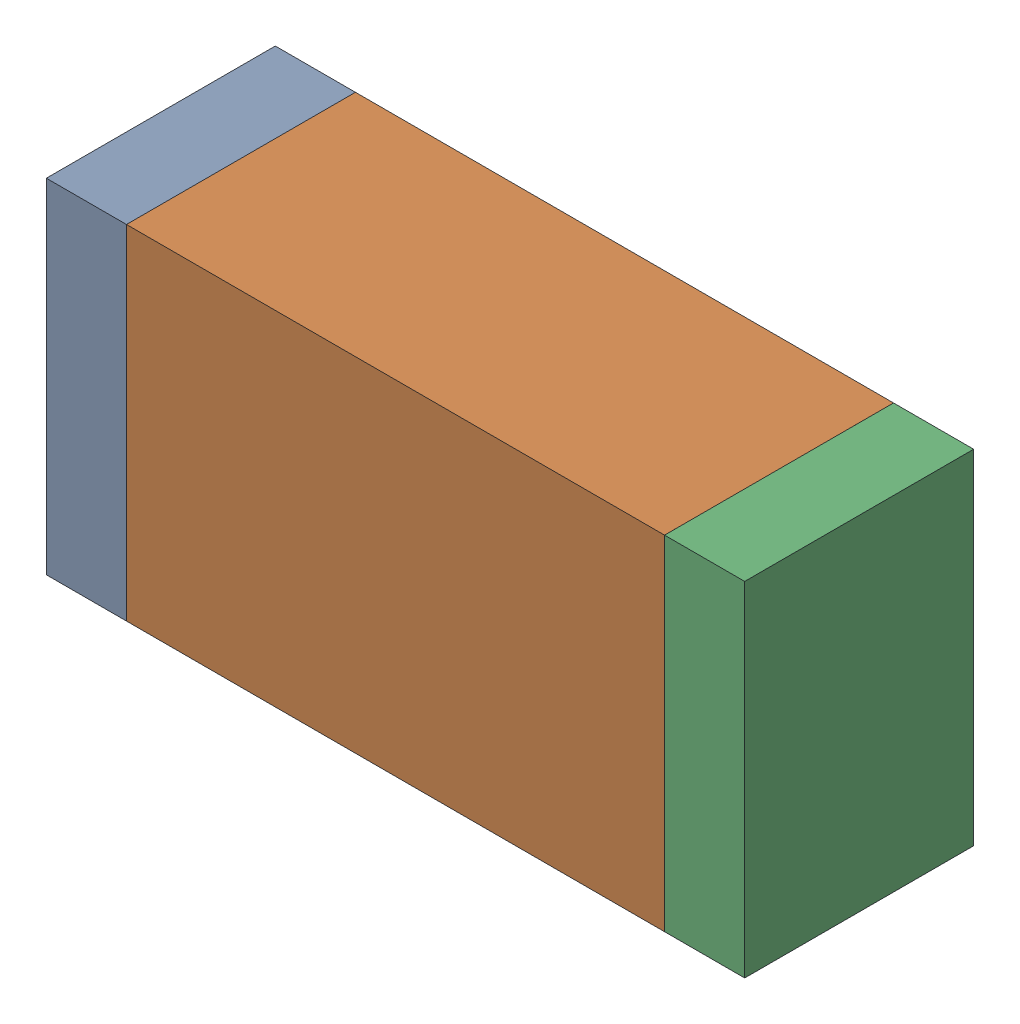
SolidWorks assembly R9, configuration Default. Lengths in mm.
Overall size (1.55 0.76 0.51).
6 component instances, 2 part files, 0 mates.
Components (placement in the parent):
- 822490216-1: 822490216 [Default] at (1.6303 1.2545 0) size (0.18 0.76 0.51)
  - Extruded-1: Extruded [Default] at origin size (0.18 0.76 0.51)
- 822498920-1: 822498920 [Default] at (2.3161 1.2545 0) size (1.19 0.76 0.51)
  - Extruded_2-1: Extruded_2 [Default] at origin size (1.19 0.76 0.51)
- 822490216-2: 822490216 [Default] at (3.0019 1.2545 0) size (0.18 0.76 0.51)
  - Extruded-1: Extruded [Default] at origin size (0.18 0.76 0.51)
